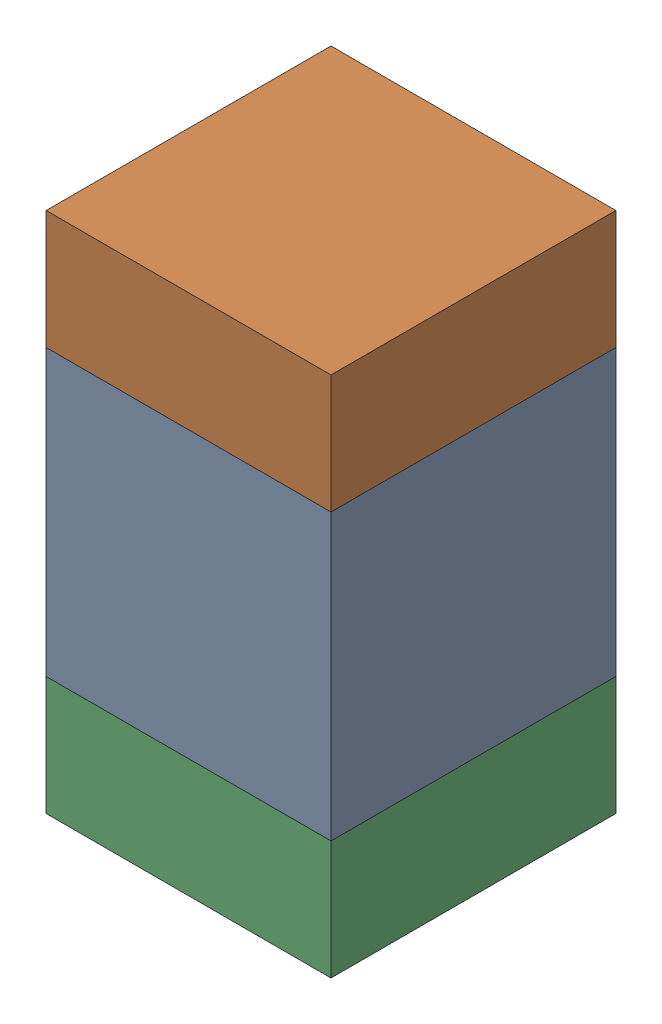
SolidWorks assembly C111_1PCB, configuration Default. Lengths in mm.
Overall size (0.6 1.1 0.6).
6 component instances, 2 part files, 0 mates.
Components (placement in the parent):
- 761606048-1: 761606048 [Default] at (116.6 115.3 0) size (0.6 0.6 0.6)
  - Extruded_9-1: Extruded_9 [Default] at origin size (0.6 0.6 0.6)
- 854785296-1: 854785296 [Default] at (116.6 115.725 0) size (0.6 0.25 0.6)
  - Extruded_10-1: Extruded_10 [Default] at origin size (0.6 0.25 0.6)
- 854785296-2: 854785296 [Default] at (116.6 114.875 0) size (0.6 0.25 0.6)
  - Extruded_10-1: Extruded_10 [Default] at origin size (0.6 0.25 0.6)
